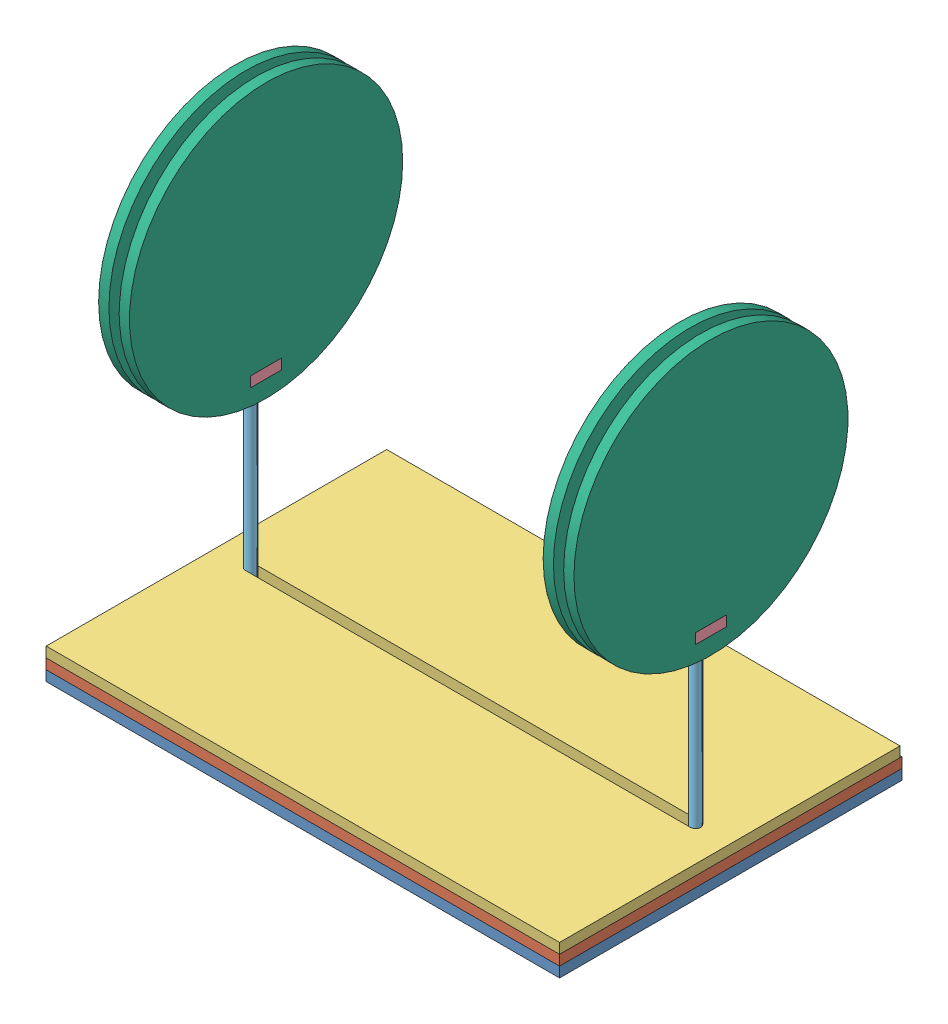
SolidWorks assembly Assem1, configuration Default. Lengths in mm.
Overall size (150 134 100).
13 component instances, 7 part files, 34 mates.
Components (placement in the parent):
- base1-1: base1 [Default] at (-5.3198 58.126 170.5863) size (150 3 100)
- base2-1: base2 [Default] at (-5.3198 61.126 170.5863) size (150 3 100)
- base3-1: base3 [Default] at (-5.3198 64.126 170.5863) size (150 3 99.48)
- joiner-1: joiner [Default] at (0.1894 120.126 125.3569) x (0 -1 0) z (0.002049 0 0.999998) size (3 9 9)
- slider-2: slider [Default] at (4.6802 64.126 120.8477) x (-0.002049 0 -0.999998) z (0.999998 0 -0.002049) size (12 62 8)
- slider-3: slider [Default] at (134.6802 64.126 120.8477) x (-0.000964 0 1) z (-1 0 -0.000964) size (12 62 8)
- joiner-2: joiner [Default] at (130.1845 117.126 116.3434) x (0 1 0) z (0.000964 0 -1) size (3 9 9)
- coilcase-1: coilcase [Default] at (9.1802 152.126 120.8385) x (0.002049 0 0.999998) z (-0.999998 0 0.002049) size (80 80 3)
- coilcase-2: coilcase [Default] at (130.1802 152.126 120.8434) x (0.000964 0 -1) z (1 0 0.000964) size (80 80 3)
- coilcase-3: coilcase [Default] at (136.1802 152.126 120.8492) x (0.000964 0 -1) z (1 0 0.000964) size (80 80 3)
- coilcase-4: coilcase [Default] at (0.1802 152.126 120.8569) x (-0.002049 0 -0.999998) z (0.999998 0 -0.002049) size (80 80 3)
- coil support-1: coil support [Default] at (3.1802 152.126 120.8508) x (-0.002049 0 -0.999998) z (0.999998 0 -0.002049) size (49.96 50 3)
- coil support-2: coil support [Default] at (133.1802 152.126 120.8463) x (0.000964 0 -1) z (1 0 0.000964) size (49.96 50 3)
Mates (geometry in assembly coordinates):
- Coincident1: coincident anti-aligned: plane of base1-1 through (-5.3198 61.126 170.5863) normal (0 1 0); plane of base2-1 through (-5.3198 61.126 170.5863) normal (0 -1 0)
- Coincident2: coincident: point of base1-1; point of base2-1
- Coincident3: coincident anti-aligned: plane of base2-1 through (-5.3198 64.126 170.5863) normal (0 1 0); plane of base3-1 through (-5.3198 64.126 170.5863) normal (0 -1 0)
- Coincident4: coincident: point of base2-1; point of base3-1
- Slot1: slot aligned: cylinder of slider-2 through (4.6802 114.126 120.8477) axis (0 -1 0) radius 1.5; cylinder of base3-1 through (4.6802 67.126 120.8477) axis (0 -1 0) radius 1.5; cylinder of base3-1 through (134.6802 67.126 120.8477) axis (0 -1 0) radius 1.5
- Coincident5: coincident anti-aligned: line of base2-1 through (-5.3198 64.126 170.5863) axis (0 0 -1); line of base3-1 through (-5.3198 64.126 71.1092) axis (0 0 1)
- Coincident6: coincident anti-aligned: plane of base3-1 through (-5.3198 64.126 170.5863) normal (0 -1 0); plane of slider-2 through (4.6802 64.126 120.8477) normal (0 1 0)
- Coincident7: coincident anti-aligned: plane of joiner-1 through (9.1894 120.126 125.3385) normal (0 1 0); plane of slider-2 through (2.1802 120.126 120.8529) normal (0 -1 0)
- Coincident8: coincident anti-aligned: line of joiner-1 through (9.1894 120.126 125.3385) axis (-0.999998 0 0.002049); line of slider-2 through (3.1894 120.126 125.3508) axis (0.999998 0 -0.002049)
- Distance1: distance = 3 mm aligned: plane of joiner-1 through (9.1894 120.126 125.3385) normal (0.999998 0 -0.002049); plane of slider-2 through (6.1802 64.126 120.8447) normal (0.999998 0 -0.002049)
- Coincident10: coincident anti-aligned: line of base1-1 through (-5.3198 61.126 70.5863) axis (0 0 1); line of base2-1 through (-5.3198 61.126 170.5863) axis (0 0 -1)
- Slot2: slot aligned: cylinder of slider-3 through (134.6802 114.126 120.8477) axis (0 -1 0) radius 1.5; cylinder of base3-1 through (134.6802 67.126 120.8477) axis (0 -1 0) radius 1.5; cylinder of base3-1 through (4.6802 67.126 120.8477) axis (0 -1 0) radius 1.5
- Coincident11: coincident anti-aligned: plane of base3-1 through (-5.3198 64.126 170.5863) normal (0 -1 0); plane of slider-3 through (134.6802 64.126 120.8477) normal (0 1 0)
- Coincident12: coincident anti-aligned: plane of slider-3 through (137.1802 120.126 120.8501) normal (0 -1 0); plane of joiner-2 through (139.1845 120.126 116.3521) normal (0 1 0)
- Coincident13: coincident aligned: line of slider-3 through (136.1845 120.126 116.3492) axis (-1 0 -0.000964); line of joiner-2 through (139.1845 120.126 116.3521) axis (-1 0 -0.000964)
- Distance2: distance = 3 mm aligned: plane of joiner-2 through (130.1845 117.126 116.3434) normal (-1 0 -0.000964); plane of slider-3 through (133.1802 64.126 120.8463) normal (-1 0 -0.000964)
- Coincident16: coincident aligned: plane of joiner-2 through (130.1845 117.126 116.3434) normal (-1 0 -0.000964); plane of coilcase-2 through (130.1802 152.126 120.8434) normal (-1 0 -0.000964)
- Coincident17: coincident aligned: line of joiner-2 through (130.1845 120.126 116.3434) axis (-0.000964 0 1); line of coilcase-2 through (130.1845 120.126 116.3434) axis (-0.000964 0 1)
- Coincident18: coincident anti-aligned: line of joiner-2 through (130.1759 120.126 125.3434) axis (0 -1 0); line of coilcase-2 through (130.1759 117.126 125.3434) axis (0 1 0)
- Coincident20: coincident aligned: plane of joiner-2 through (139.1845 117.126 116.3521) normal (1 0 0.000964); plane of coilcase-3 through (139.1802 152.126 120.8521) normal (1 0 0.000964)
- Coincident21: coincident anti-aligned: line of joiner-2 through (139.1759 117.126 125.3521) axis (0.000964 0 -1); line of coilcase-3 through (139.1845 117.126 116.3521) axis (-0.000964 0 1)
- Coincident22: coincident anti-aligned: line of joiner-2 through (139.1759 120.126 125.3521) axis (0 -1 0); line of coilcase-3 through (139.1759 117.126 125.3521) axis (0 1 0)
- Coincident23: coincident aligned: plane of joiner-1 through (9.1894 120.126 125.3385) normal (0.999998 0 -0.002049); plane of coilcase-1 through (9.1802 152.126 120.8385) normal (0.999998 0 -0.002049)
- Coincident24: coincident anti-aligned: line of joiner-1 through (9.1894 120.126 125.3385) axis (0 -1 0); line of coilcase-1 through (9.1894 117.126 125.3385) axis (0 1 0)
- Coincident25: coincident anti-aligned: line of joiner-1 through (9.171 120.126 116.3385) axis (0.002049 0 0.999998); line of coilcase-1 through (9.1894 120.126 125.3385) axis (-0.002049 0 -0.999998)
- Coincident26: coincident aligned: plane of joiner-1 through (0.1894 120.126 125.3569) normal (-0.999998 0 0.002049); plane of coilcase-4 through (0.1802 152.126 120.8569) normal (-0.999998 0 0.002049)
- Coincident27: coincident anti-aligned: line of joiner-1 through (0.1894 117.126 125.3569) axis (-0.002049 0 -0.999998); line of coilcase-4 through (0.171 117.126 116.357) axis (0.002049 0 0.999998)
- Coincident28: coincident anti-aligned: line of joiner-1 through (0.1894 120.126 125.3569) axis (0 -1 0); line of coilcase-4 through (0.1894 117.126 125.3569) axis (0 1 0)
- Coincident30: coincident anti-aligned: plane of coilcase-4 through (3.1802 152.126 120.8508) normal (0.999998 0 -0.002049); plane of coil support-1 through (3.1802 152.126 120.8508) normal (-0.999998 0 0.002049)
- Coincident31: coincident anti-aligned: plane of coilcase-2 through (133.1802 152.126 120.8463) normal (1 0 0.000964); plane of coil support-2 through (133.1802 152.126 120.8463) normal (-1 0 -0.000964)
- Parallel2: parallel anti-aligned: plane of base3-1 through (-5.3198 67.126 170.5863) normal (0 1 0); plane of coil support-2 through (136.1802 153.126 120.8492) normal (0 -1 0)
- Concentric4: concentric aligned: circle of coilcase-2; circle of coil support-2
- Parallel3: parallel anti-aligned: plane of base3-1 through (-5.3198 67.126 170.5863) normal (0 1 0); plane of coil support-1 through (6.1802 153.126 120.8447) normal (0 -1 0)
- Concentric5: concentric aligned: circle of coilcase-4; circle of coil support-1
